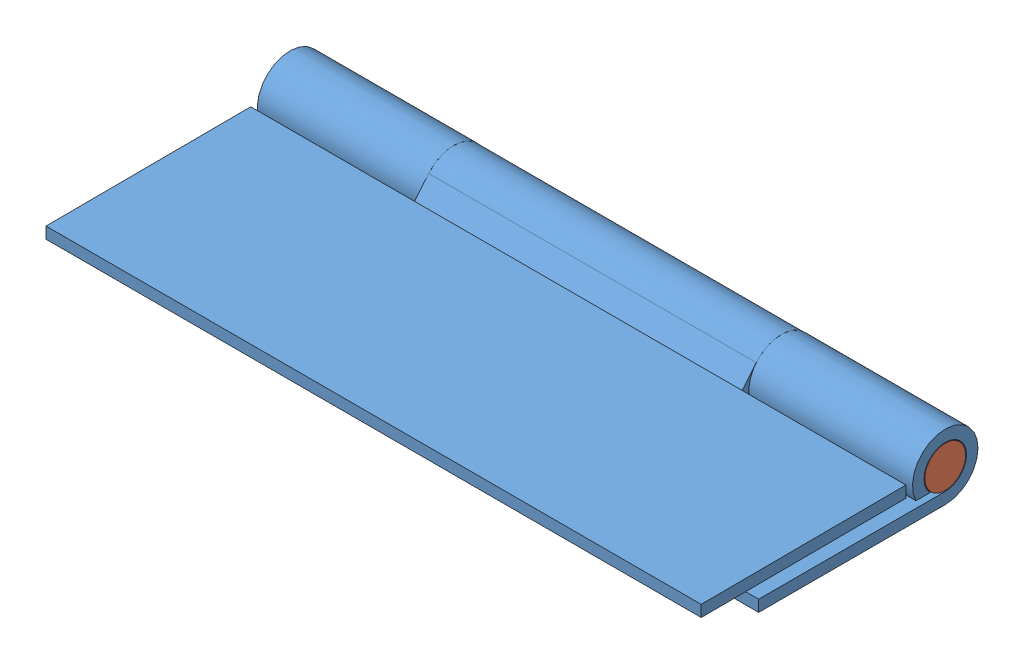
SolidWorks assembly Part15_HingeAsm, configuration Default. Lengths in mm.
Overall size (50.8 5.18 21.49).
3 component instances, 2 part files, 3 mates.
Components (placement in the parent):
- Part15Hinge-1: Part15Hinge [Sides] at (-6.04 23.5256 50.198) size (50.8 5.08 17.01)
- Part15Hinge-2: Part15Hinge [Mid] at (44.76 26.2963 50.2073) x (-1 0 0) z (0 -0.00467 0.999989) size (50.8 5.08 21.46)
- Part15HingePin-1: Part15HingePin [Default] at (-6.04 26.3833 35.2528) x (0 -0.757668 -0.65264) z (1 0 0) size (3.17 3.17 50.8)
Mates (geometry in assembly coordinates):
- Hinge1: hinge aligned: cylinder of Part15Hinge-1 through (52.3061 26.0656 31.283) axis (-1 0 0) radius 2.54; cylinder of Part15Hinge-2 through (32.06 26.0656 31.283) axis (-1 0 0) radius 2.54; plane of Part15Hinge-1 through (44.76 24.4146 50.198) normal (1 0 0); plane of Part15Hinge-2 through (44.76 25.4073 50.2031) normal (1 0 0)
- Concentric2: concentric aligned: cylinder of Part15HingePin-1 through (44.76 26.0656 31.283) axis (-1 0 0) radius 1.5875; cylinder of Part15Hinge-1 through (52.3061 26.0656 31.283) axis (-1 0 0) radius 1.651
- Coincident4: coincident aligned: plane of Part15Hinge-1 through (44.76 24.4146 50.198) normal (1 0 0); plane of Part15HingePin-1 through (44.76 26.0656 31.283) normal (1 0 0)
